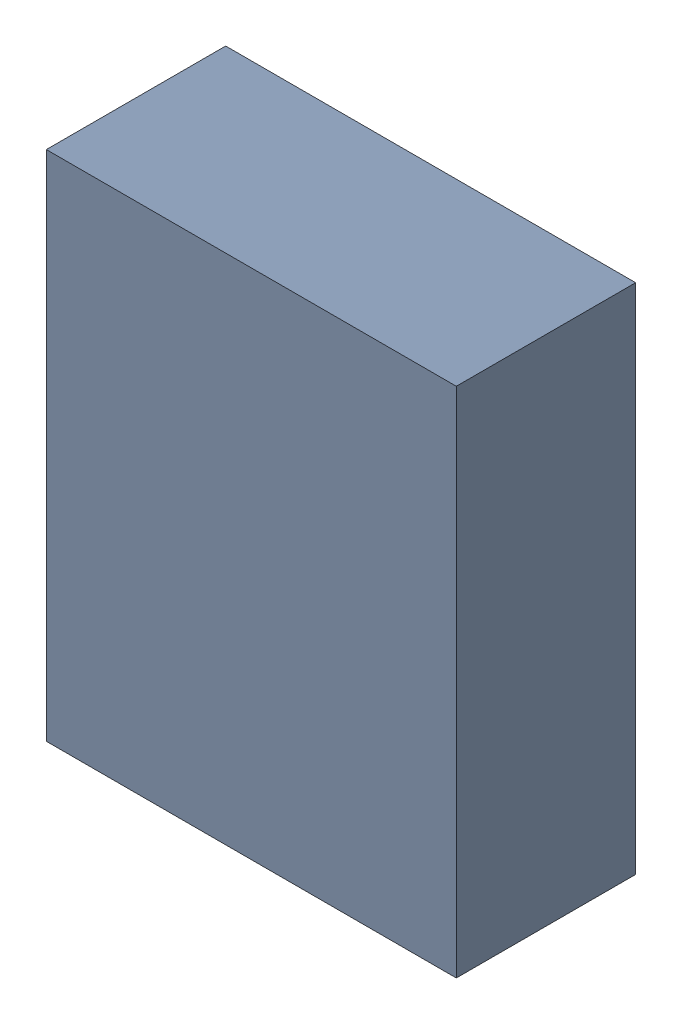
SolidWorks assembly U12, configuration ﾃﾞﾌｫﾙﾄ. Lengths in mm.
Overall size (4 5 1.75).
2 component instances, 1 part files, 0 mates.
Components (placement in the parent):
- 689262464-1: 689262464 [ﾃﾞﾌｫﾙﾄ] at (51.1175 48.5775 0) size (4 5 1.75)
  - Extruded_40-1: Extruded_40 [ﾃﾞﾌｫﾙﾄ] at origin size (4 5 1.75)
